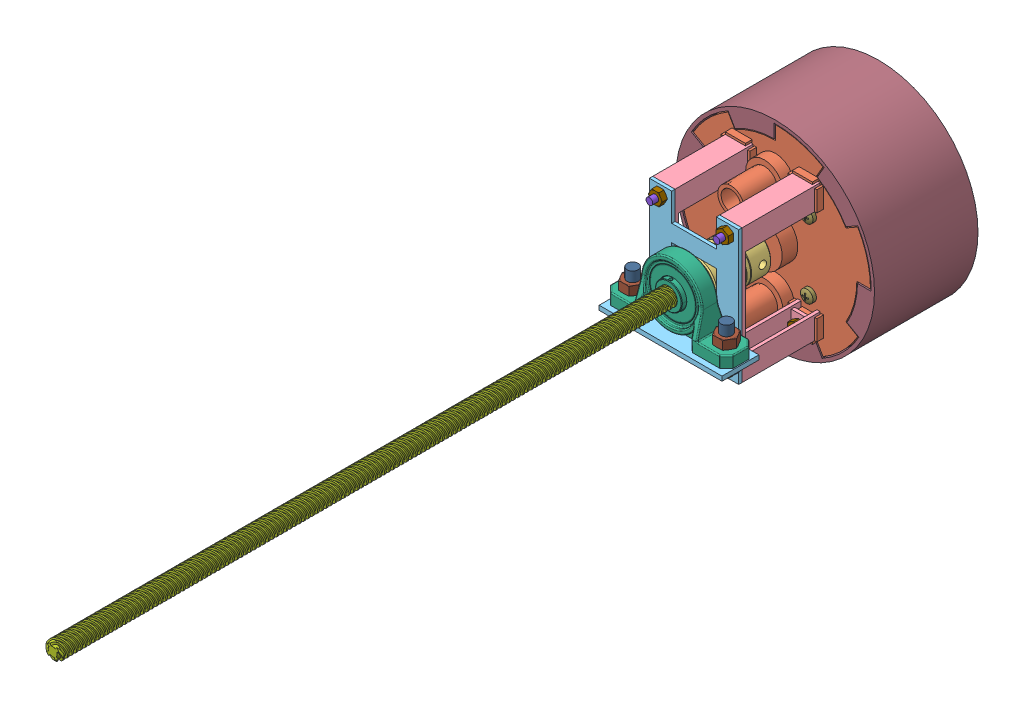
SolidWorks assembly Acopladores, configuration Valor predeterminado. Lengths in mm.
Overall size (89 89 371.91).
33 component instances, 13 part files, 68 mates.
Components (placement in the parent):
- Motor - Gerson2-1: Motor - Gerson2 [Valor predeterminado] at (56.2758 -44.2571 -1.6226) size (41 47 59.5)
- 12L - Acoplador Nema-Eixo-1: 12L - Acoplador Nema-Eixo [Valor predeterminado] at (58.1232 -52.7558 35.1774) x (0 1 0) z (0 0 -1) size (85 85 35)
- Acoplador_5_8-1: Acoplador_5_8 [Default] at (58.1232 -52.7558 46.3774) x (0 0 1) z (-0.045854 0.998948 0) size (25 19.74 19.74)
- 8H - Base suporte mancal inferior-1: 8H - Base suporte mancal inferior [Valor predeterminado] at (58.1232 -52.7558 35.1774) x (0 1 0) z (0 0 -1) size (60 40 35)
- 3C - Suporte mancal inferior-1: 3C - Suporte mancal inferior [Valor predeterminado] at (58.1232 -52.7558 35.1774) x (0 -1 0) z (0 0 -1) size (60 55 16.5)
- Mancal-1: Mancal [Valor predeterminado] at (58.1232 -52.7558 78.1774) size (55 28.75 13.77)
- Fuso_TR8x2x300-1: Fuso_TR8x2x300 [Valor predeterminado] at (59.1846 -50.5793 -95.2386) x (0.121188 0.99263 0) z (0 0 1) size (10 10 304.12)
  - Fuso trapezoidal TR8_Passo 2mm - Passo total 8mm -1: Fuso trapezoidal TR8_Passo 2mm - Passo total 8mm  [Valor predeterminado] at (-2.2891 0.7898 304.116) size (10 10 304.12)
- M3x8-2: M3x8 [Default] at (73.1232 -26.7413 68.6774) x (0 0 1) z (0 -1 0) size (10.37 5.6 5.6)
- M3x8-3: M3x8 [Default] at (43.1232 -26.7413 68.6774) x (0 0 1) z (-1 0 0) size (10.37 5.6 5.6)
- M3x8-4: M3x8 [Default] at (73.1232 -78.7703 68.6774) x (0 0 1) z (-1 0 0) size (10.37 5.6 5.6)
- M3x8-5: M3x8 [Default] at (43.1232 -78.7703 68.6774) x (0 0 1) z (-1 0 0) size (10.37 5.6 5.6)
- Porca M3-2: Porca M3 [Default] at (43.1232 -26.7413 71.6774) x (0 0 1) z (0 -1 0) size (2.41 6.36 6.36)
- Porca M3-3: Porca M3 [Default] at (43.1232 -78.7703 74.0774) x (0 0 -1) z (1 0 0) size (2.41 6.36 6.36)
- Porca M3-4: Porca M3 [Default] at (73.1232 -26.7413 74.0774) x (0 0 -1) z (1 0 0) size (2.41 6.36 6.36)
- Porca M3-5: Porca M3 [Default] at (73.1232 -78.7703 74.0774) x (0 0 -1) z (1 0 0) size (2.41 6.36 6.36)
- M5x16-1: M5x16 [Default] at (79.1232 -70.2558 78.1774) x (0 1 0) z (0 0 1) size (19.66 9.5 9.5)
- M5x16-2: M5x16 [Default] at (37.1232 -70.2558 78.1774) x (0 1 0) z (0 0 1) size (19.66 9.5 9.5)
- Porca M5-3: Porca M5 [Default] at (79.1232 -62.7558 78.1774) x (0 1 0) z (0 0 1) size (4.01 9.25 9.25)
- Porca M5-4: Porca M5 [Default] at (37.1232 -62.7558 78.1774) x (0 1 0) z (0 0 1) size (4.01 9.25 9.25)
- M3x12-3: M3x12 [Default] at (73.1232 -78.7703 33.6774) x (0 0 1) z (0.247227 -0.968958 0) size (14.37 5.6 5.6)
- M3x12-4: M3x12 [Default] at (43.1232 -78.7703 33.6774) x (0 0 1) z (-1 0 0) size (14.37 5.6 5.6)
- M3x12-5: M3x12 [Default] at (73.1232 -26.7413 33.6774) x (0 0 1) z (-1 0 0) size (14.37 5.6 5.6)
- M3x12-6: M3x12 [Default] at (43.1232 -26.7413 33.6774) x (0 0 1) z (-1 0 0) size (14.37 5.6 5.6)
- Porca M3-6: Porca M3 [Default] at (43.1232 -26.7413 42.0774) x (0 0 -1) z (0.37485 -0.927086 0) size (2.41 6.36 6.36)
- Porca M3-7: Porca M3 [Default] at (73.1232 -26.7413 42.0774) x (0 0 -1) z (1 0 0) size (2.41 6.36 6.36)
- Porca M3-8: Porca M3 [Default] at (43.1232 -78.7703 42.0774) x (0 0 -1) z (1 0 0) size (2.41 6.36 6.36)
- Porca M3-9: Porca M3 [Default] at (73.1232 -78.7703 42.0774) x (0 0 -1) z (1 0 0) size (2.41 6.36 6.36)
- M3x12-7: M3x12 [Default] at (73.6232 -37.2558 35.1774) x (0 0 -1) z (1 0 0) size (14.37 5.6 5.6)
- M3x12-8: M3x12 [Default] at (73.6232 -68.2558 35.1774) x (0 0 -1) z (1 0 0) size (14.37 5.6 5.6)
- M3x12-9: M3x12 [Default] at (42.6232 -37.2558 35.1774) x (0 0 -1) z (1 0 0) size (14.37 5.6 5.6)
- M3x12-10: M3x12 [Default] at (42.6232 -68.2558 35.1774) x (0 0 -1) z (1 0 0) size (14.37 5.6 5.6)
- 11K - Acoplador Servo-Nema-2: 11K - Acoplador Servo-Nema [Valor predeterminado] at (58.1232 -52.7558 35.3774) x (0 1 0) z (0 0 -1) size (89 89 46.35)
Mates (geometry in assembly coordinates):
- Concêntrico1: concentric aligned: cylinder of Motor - Gerson2-1 through (73.6232 -68.2558 31.3774) axis (0 0 1) radius 1.25; cylinder of 12L - Acoplador Nema-Eixo-1 through (73.6232 -68.2558 20.1774) axis (0 0 1) radius 1.65
- Concêntrico2: concentric aligned: cylinder of Motor - Gerson2-1 through (42.6232 -37.2558 31.3774) axis (0 0 1) radius 1.25; cylinder of 12L - Acoplador Nema-Eixo-1 through (42.6232 -37.2558 20.1774) axis (0 0 1) radius 1.65
- Coincidente1: coincident anti-aligned: plane of Motor - Gerson2-1 through (56.2758 -44.2571 31.3774) normal (0 0 1); plane of 12L - Acoplador Nema-Eixo-1 through (58.1232 -52.7558 31.3774) normal (0 0 -1)
- Concêntrico3: concentric aligned: cylinder of Motor - Gerson2-1 through (58.1232 -52.7558 70.3774) axis (0 0 -1) radius 2.5; cylinder of Acoplador_5_8-1 through (58.1232 -52.7558 71.3774) axis (0 0 -1) radius 2.5
- Coincidente2: coincident aligned: circle of Motor - Gerson2-1; plane of Acoplador_5_8-1 through (58.1232 -52.7558 46.3774) normal (0 0 -1)
- Coincidente3: coincident aligned: circle of 12L - Acoplador Nema-Eixo-1; cylinder of 8H - Base suporte mancal inferior-1 through (73.1232 -78.7703 21.6774) axis (0 0 1) radius 1.65
- Concêntrico4: concentric anti-aligned: circle of 12L - Acoplador Nema-Eixo-1; circle of 8H - Base suporte mancal inferior-1
- Coincidente5: coincident anti-aligned: plane of 12L - Acoplador Nema-Eixo-1 through (58.1232 -52.7558 35.1774) normal (0 0 1); plane of 8H - Base suporte mancal inferior-1 through (58.1232 -52.7558 35.1774) normal (0 0 -1)
- Concêntrico5: concentric: cylinder of 8H - Base suporte mancal inferior-1 through (73.1232 -78.7703 21.6774) axis (0 0 1) radius 1.65; cylinder of 3C - Suporte mancal inferior-1 through (73.1232 -78.7703 21.6774) axis (0 0 1) radius 1.65
- Concêntrico6: concentric aligned: cylinder of 8H - Base suporte mancal inferior-1 through (43.1232 -26.7413 21.6774) axis (0 0 1) radius 1.65; cylinder of 3C - Suporte mancal inferior-1 through (43.1232 -26.7413 21.6774) axis (0 0 1) radius 1.65
- Coincidente6: coincident anti-aligned: plane of 8H - Base suporte mancal inferior-1 through (58.1232 -52.7558 70.1774) normal (0 0 1); plane of 3C - Suporte mancal inferior-1 through (58.1232 -52.7558 70.1774) normal (0 0 -1)
- Concêntrico7: concentric aligned: cylinder of 3C - Suporte mancal inferior-1 through (79.1232 -97.2558 78.1774) axis (0 1 0) radius 2.65; cylinder of Mancal-1 through (79.1232 -67.7558 78.1774) axis (0 1 0) radius 2.5
- Concêntrico8: concentric aligned: cylinder of 3C - Suporte mancal inferior-1 through (37.1232 -97.2558 78.1774) axis (0 1 0) radius 2.65; cylinder of Mancal-1 through (37.1232 -67.7558 78.1774) axis (0 1 0) radius 2.5
- Concêntrico12: concentric aligned: cylinder of Acoplador_5_8-1 through (58.1232 -52.7558 71.3774) axis (0 0 -1) radius 9.5; cylinder of Fuso_TR8x2x300-1/Fuso trapezoidal TR8_Passo 2mm - Passo total 8mm -1 through (58.1232 -52.7558 358.8774) axis (0 0 -1) radius 4
- Concêntrico13: concentric anti-aligned: cylinder of Mancal-1 through (58.1232 -52.7558 58.2068) axis (0 0 1) radius 4; cylinder of Fuso_TR8x2x300-1/Fuso trapezoidal TR8_Passo 2mm - Passo total 8mm -1 through (58.1232 -52.7558 358.8774) axis (0 0 -1) radius 4
- Coincidente8: coincident anti-aligned: plane of Acoplador_5_8-1 through (58.1232 -52.7558 58.8774) normal (0 0 1); plane of Fuso_TR8x2x300-1/Fuso trapezoidal TR8_Passo 2mm - Passo total 8mm -1 through (58.1232 -52.7558 58.8774) normal (0 0 -1)
- Parafuso1: screw = 1 aligned: cylinder of Acoplador_5_8-1 through (58.1232 -52.7558 71.3774) axis (0 0 -1) radius 9.5; cylinder of Fuso_TR8x2x300-1/Fuso trapezoidal TR8_Passo 2mm - Passo total 8mm -1 through (58.1232 -52.7558 358.8774) axis (0 0 -1) radius 4
- Coincidente12: coincident aligned: plane of M3x8-2 through (70.8232 -26.7413 68.6774) normal (0 0 1); plane of M3x8-3 through (43.1232 -24.4413 68.6774) normal (0 0 1)
- Coincidente13: coincident aligned: plane of M3x8-3 through (43.1232 -24.4413 68.6774) normal (0 0 1); plane of M3x8-5 through (43.1232 -76.4703 68.6774) normal (0 0 1)
- Coincidente14: coincident aligned: plane of M3x8-4 through (73.1232 -76.4703 68.6774) normal (0 0 1); plane of M3x8-5 through (43.1232 -76.4703 68.6774) normal (0 0 1)
- Concêntrico19: concentric anti-aligned: cylinder of 3C - Suporte mancal inferior-1 through (73.1232 -78.7703 21.6774) axis (0 0 1) radius 1.65; cylinder of M3x8-4 through (73.1232 -78.7703 73.1774) axis (0 0 -1) radius 1.5
- Concêntrico20: concentric anti-aligned: cylinder of 3C - Suporte mancal inferior-1 through (43.1232 -78.7703 21.6774) axis (0 0 1) radius 1.65; cylinder of M3x8-5 through (43.1232 -78.7703 73.1774) axis (0 0 -1) radius 1.5
- Concêntrico21: concentric anti-aligned: cylinder of 3C - Suporte mancal inferior-1 through (43.1232 -26.7413 21.6774) axis (0 0 1) radius 1.65; cylinder of M3x8-3 through (43.1232 -26.7413 73.1774) axis (0 0 -1) radius 1.5
- Concêntrico22: concentric anti-aligned: cylinder of 3C - Suporte mancal inferior-1 through (73.1232 -26.7413 21.6774) axis (0 0 1) radius 1.65; cylinder of M3x8-2 through (73.1232 -26.7413 73.1774) axis (0 0 -1) radius 1.5
- Coincidente15: coincident anti-aligned: plane of 8H - Base suporte mancal inferior-1 through (58.1232 -52.7558 68.6774) normal (0 0 -1); plane of M3x8-3 through (43.1232 -24.4413 68.6774) normal (0 0 1)
- Coincidente16: coincident aligned: plane of Porca M3-4 through (73.1232 -26.7413 74.0774) normal (0 0 1); plane of Porca M3-5 through (73.1232 -78.7703 74.0774) normal (0 0 1)
- Coincidente17: coincident aligned: plane of Porca M3-3 through (43.1232 -78.7703 74.0774) normal (0 0 1); plane of Porca M3-5 through (73.1232 -78.7703 74.0774) normal (0 0 1)
- Coincidente18: coincident aligned: plane of Porca M3-2 through (40.3732 -26.7413 74.0774) normal (0 0 1); plane of Porca M3-3 through (43.1232 -78.7703 74.0774) normal (0 0 1)
- Concêntrico23: concentric anti-aligned: cylinder of M3x8-4 through (73.1232 -78.7703 73.1774) axis (0 0 -1) radius 1.5; cylinder of Porca M3-5 through (73.1232 -78.7703 71.6774) axis (0 0 1) radius 1.2295
- Concêntrico24: concentric anti-aligned: cylinder of M3x8-2 through (73.1232 -26.7413 73.1774) axis (0 0 -1) radius 1.5; cylinder of Porca M3-4 through (73.1232 -26.7413 71.6774) axis (0 0 1) radius 1.2295
- Concêntrico25: concentric aligned: cylinder of M3x8-3 through (43.1232 -26.7413 73.1774) axis (0 0 -1) radius 1.5; cylinder of Porca M3-2 through (43.1232 -26.7413 74.0774) axis (0 0 -1) radius 1.2295
- Concêntrico26: concentric anti-aligned: cylinder of M3x8-5 through (43.1232 -78.7703 73.1774) axis (0 0 -1) radius 1.5; cylinder of Porca M3-3 through (43.1232 -78.7703 71.6774) axis (0 0 1) radius 1.2295
- Coincidente19: coincident anti-aligned: plane of 3C - Suporte mancal inferior-1 through (58.1232 -52.7558 71.6774) normal (0 0 1); plane of Porca M3-3 through (43.1232 -76.0203 71.6774) normal (0 0 -1)
- Concêntrico33: concentric aligned: cylinder of M5x16-2 through (37.1232 -61.4558 78.1774) axis (0 -1 0) radius 2.5; cylinder of Porca M5-4 through (37.1232 -58.7558 78.1774) axis (0 -1 0) radius 2.067
- Concêntrico34: concentric aligned: cylinder of M5x16-1 through (79.1232 -61.4558 78.1774) axis (0 -1 0) radius 2.5; cylinder of Porca M5-3 through (79.1232 -58.7558 78.1774) axis (0 -1 0) radius 2.067
- Coincidente26: coincident aligned: plane of Porca M5-3 through (75.1232 -58.7558 78.1774) normal (0 1 0); plane of Porca M5-4 through (33.1232 -58.7558 78.1774) normal (0 1 0)
- Coincidente27: coincident aligned: plane of M5x16-1 through (75.3232 -70.2558 78.1774) normal (0 1 0); plane of M5x16-2 through (33.3232 -70.2558 78.1774) normal (0 1 0)
- Concêntrico35: concentric anti-aligned: cylinder of Mancal-1 through (79.1232 -67.7558 78.1774) axis (0 1 0) radius 2.5; cylinder of M5x16-1 through (79.1232 -61.4558 78.1774) axis (0 -1 0) radius 2.5
- Concêntrico36: concentric anti-aligned: cylinder of Mancal-1 through (37.1232 -67.7558 78.1774) axis (0 1 0) radius 2.5; cylinder of M5x16-2 through (37.1232 -61.4558 78.1774) axis (0 -1 0) radius 2.5
- Coincidente28: coincident anti-aligned: plane of Mancal-1 through (85.6232 -62.7558 84.6774) normal (0 1 0); plane of Porca M5-3 through (79.1232 -62.7558 78.1774) normal (0 -1 0)
- Coincidente29: coincident anti-aligned: plane of 3C - Suporte mancal inferior-1 through (48.1232 -70.2558 71.6774) normal (0 -1 0); plane of M5x16-1 through (75.3232 -70.2558 78.1774) normal (0 1 0)
- Coincidente36: coincident aligned: plane of M3x12-3 through (72.3965 -78.9558 45.6774) normal (0 0 1); plane of M3x12-4 through (43.1232 -78.0203 45.6774) normal (0 0 1)
- Coincidente37: coincident aligned: plane of M3x12-5 through (73.1232 -25.9913 45.6774) normal (0 0 1); plane of M3x12-6 through (43.1232 -25.9913 45.6774) normal (0 0 1)
- Coincidente38: coincident aligned: plane of M3x12-4 through (43.1232 -78.0203 45.6774) normal (0 0 1); plane of M3x12-6 through (43.1232 -25.9913 45.6774) normal (0 0 1)
- Coincidente39: coincident aligned: plane of Porca M3-8 through (43.1232 -78.7703 42.0774) normal (0 0 1); plane of Porca M3-9 through (73.1232 -78.7703 42.0774) normal (0 0 1)
- Coincidente40: coincident aligned: plane of Porca M3-6 through (43.1232 -26.7413 42.0774) normal (0 0 1); plane of Porca M3-7 through (73.1232 -26.7413 42.0774) normal (0 0 1)
- Coincidente41: coincident aligned: plane of Porca M3-7 through (73.1232 -26.7413 42.0774) normal (0 0 1); plane of Porca M3-8 through (43.1232 -78.7703 42.0774) normal (0 0 1)
- Concêntrico39: concentric anti-aligned: cylinder of 12L - Acoplador Nema-Eixo-1 through (73.1232 -26.7413 21.6774) axis (0 0 1) radius 1.65; cylinder of M3x12-5 through (73.1232 -26.7413 40.1774) axis (0 0 -1) radius 1.5
- Concêntrico40: concentric anti-aligned: cylinder of 12L - Acoplador Nema-Eixo-1 through (43.1232 -26.7413 21.6774) axis (0 0 1) radius 1.65; cylinder of M3x12-6 through (43.1232 -26.7413 40.1774) axis (0 0 -1) radius 1.5
- Concêntrico41: concentric anti-aligned: cylinder of 12L - Acoplador Nema-Eixo-1 through (43.1232 -78.7703 21.6774) axis (0 0 1) radius 1.65; cylinder of M3x12-4 through (43.1232 -78.7703 40.1774) axis (0 0 -1) radius 1.5
- Concêntrico42: concentric anti-aligned: cylinder of 12L - Acoplador Nema-Eixo-1 through (73.1232 -78.7703 21.6774) axis (0 0 1) radius 1.65; cylinder of M3x12-3 through (73.1232 -78.7703 40.1774) axis (0 0 -1) radius 1.5
- Coincidente42: coincident anti-aligned: plane of 12L - Acoplador Nema-Eixo-1 through (58.1232 -52.7558 33.6774) normal (0 0 -1); plane of M3x12-3 through (70.8946 -79.339 33.6774) normal (0 0 1)
- Concêntrico43: concentric anti-aligned: cylinder of M3x12-3 through (73.1232 -78.7703 40.1774) axis (0 0 -1) radius 1.5; cylinder of Porca M3-9 through (73.1232 -78.7703 39.6774) axis (0 0 1) radius 1.2295
- Concêntrico44: concentric anti-aligned: cylinder of M3x12-4 through (43.1232 -78.7703 40.1774) axis (0 0 -1) radius 1.5; cylinder of Porca M3-8 through (43.1232 -78.7703 39.6774) axis (0 0 1) radius 1.2295
- Concêntrico45: concentric anti-aligned: cylinder of M3x12-5 through (73.1232 -26.7413 40.1774) axis (0 0 -1) radius 1.5; cylinder of Porca M3-7 through (73.1232 -26.7413 39.6774) axis (0 0 1) radius 1.2295
- Concêntrico46: concentric anti-aligned: cylinder of M3x12-6 through (43.1232 -26.7413 40.1774) axis (0 0 -1) radius 1.5; cylinder of Porca M3-6 through (43.1232 -26.7413 39.6774) axis (0 0 1) radius 1.2295
- Coincidente43: coincident anti-aligned: plane of 8H - Base suporte mancal inferior-1 through (58.1232 -52.7558 39.6774) normal (0 0 1); plane of Porca M3-6 through (45.6727 -25.7104 39.6774) normal (0 0 -1)
- Coincidente44: coincident aligned: plane of M3x12-8 through (73.6232 -65.9558 35.1774) normal (0 0 -1); plane of M3x12-9 through (42.6232 -34.9558 35.1774) normal (0 0 -1)
- Coincidente45: coincident aligned: plane of M3x12-7 through (73.6232 -34.9558 35.1774) normal (0 0 -1); plane of M3x12-8 through (73.6232 -65.9558 35.1774) normal (0 0 -1)
- Coincidente46: coincident aligned: plane of M3x12-7 through (73.6232 -34.9558 35.1774) normal (0 0 -1); plane of M3x12-10 through (42.6232 -65.9558 35.1774) normal (0 0 -1)
- Concêntrico47: concentric aligned: cylinder of 12L - Acoplador Nema-Eixo-1 through (42.6232 -37.2558 20.1774) axis (0 0 1) radius 1.65; cylinder of M3x12-9 through (42.6232 -37.2558 28.6774) axis (0 0 1) radius 1.5
- Concêntrico48: concentric aligned: cylinder of 12L - Acoplador Nema-Eixo-1 through (42.6232 -68.2558 20.1774) axis (0 0 1) radius 1.65; cylinder of M3x12-10 through (42.6232 -68.2558 28.6774) axis (0 0 1) radius 1.5
- Concêntrico49: concentric aligned: cylinder of 12L - Acoplador Nema-Eixo-1 through (73.6232 -37.2558 20.1774) axis (0 0 1) radius 1.65; cylinder of M3x12-7 through (73.6232 -37.2558 28.6774) axis (0 0 1) radius 1.5
- Concêntrico50: concentric aligned: cylinder of 12L - Acoplador Nema-Eixo-1 through (73.6232 -68.2558 20.1774) axis (0 0 1) radius 1.65; cylinder of M3x12-8 through (73.6232 -68.2558 28.6774) axis (0 0 1) radius 1.5
- Coincidente47: coincident anti-aligned: plane of 12L - Acoplador Nema-Eixo-1 through (58.1232 -52.7558 35.1774) normal (0 0 1); plane of M3x12-9 through (42.6232 -34.9558 35.1774) normal (0 0 -1)
- Concêntrico51: concentric aligned: cylinder of 12L - Acoplador Nema-Eixo-1 through (58.1232 -52.7558 33.6774) axis (0 0 1) radius 42.5; cylinder of 11K - Acoplador Servo-Nema-2 through (58.1232 -52.7558 -10.9726) axis (0 0 1) radius 44.5
- Coincidente48: coincident anti-aligned: plane of Motor - Gerson2-1 through (56.2758 -44.2571 -1.6226) normal (0 0 -1); plane of 11K - Acoplador Servo-Nema-2 through (58.1232 -52.7558 -1.6226) normal (0 0 1)
- Paralelo2: parallel anti-aligned: plane of 12L - Acoplador Nema-Eixo-1 through (94.5232 -52.7558 33.6774) normal (0 -1 0); plane of 11K - Acoplador Servo-Nema-2 through (95.0198 -53.2558 -10.9726) normal (0 1 0)
